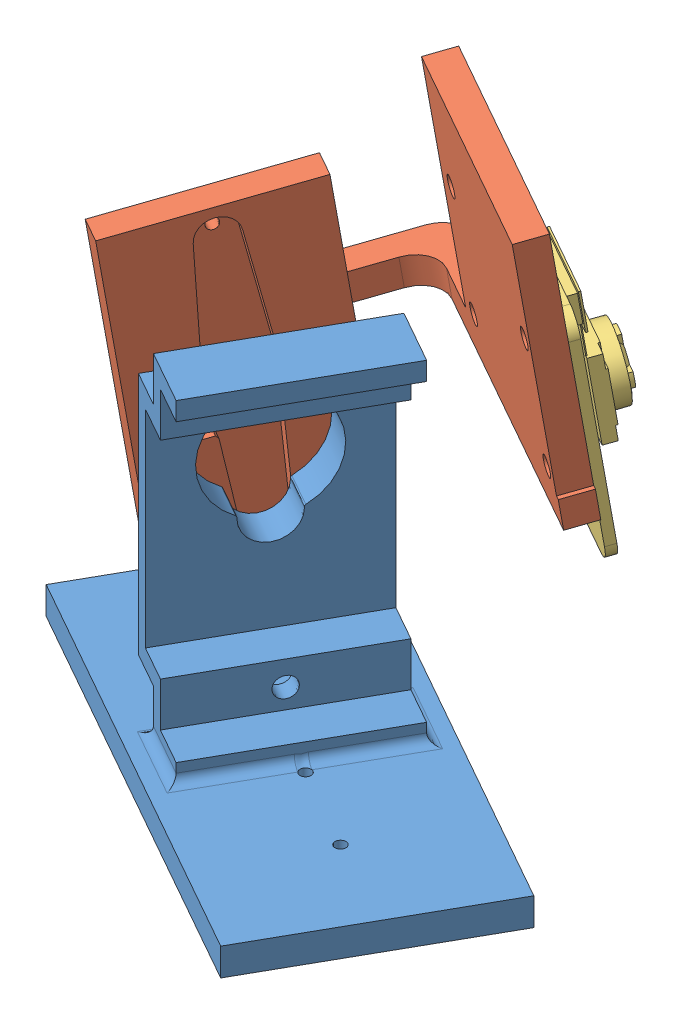
SolidWorks assembly Montaj_v_1_3, configuration Varsayılan. Lengths in mm.
Overall size (57.07 55.13 56.65).
3 component instances, 3 part files, 2 mates.
Components (placement in the parent):
- pervane_v1_2-2: pervane_v1_2 [Varsayılan] at (-643.6971 30.85 -6.0095) x (-0.870948 0 -0.491375) z (0.491375 0 -0.870948) size (50 39.1 25)
- deneme2-1: deneme2 [Varsayılan] at (-654.2358 57.0499 -11.9553) x (-0.070571 0.989637 0.125057) z (-0.486281 -0.143595 0.861923) size (43.16 38 30.95)
- Cam V2.1 v1-1: Cam V2.1 v1 [Varsayılan] at (-634.5736 65.5793 -24.3855) x (0.486281 0.143595 -0.861923) z (0.870948 0.000014 0.491375) size (6.48 24.01 25.01)
Mates (geometry in assembly coordinates):
- Coincident1: coincident anti-aligned: plane of deneme2-1 through (-656.0632 61.6214 -37.1689) normal (0.486281 0.143595 -0.861923); plane of Cam V2.1 v1-1 through (-634.5736 65.5793 -24.3855) normal (-0.486281 -0.143595 0.861923)
- Concentric2: concentric aligned: cylinder of deneme2-1 through (-647.2585 74.6386 -23.2707) axis (0.486281 0.143595 -0.861923) radius 1; cylinder of Cam V2.1 v1-1 through (-644.4242 75.4755 -28.2943) axis (0.486281 0.143595 -0.861923) radius 1
